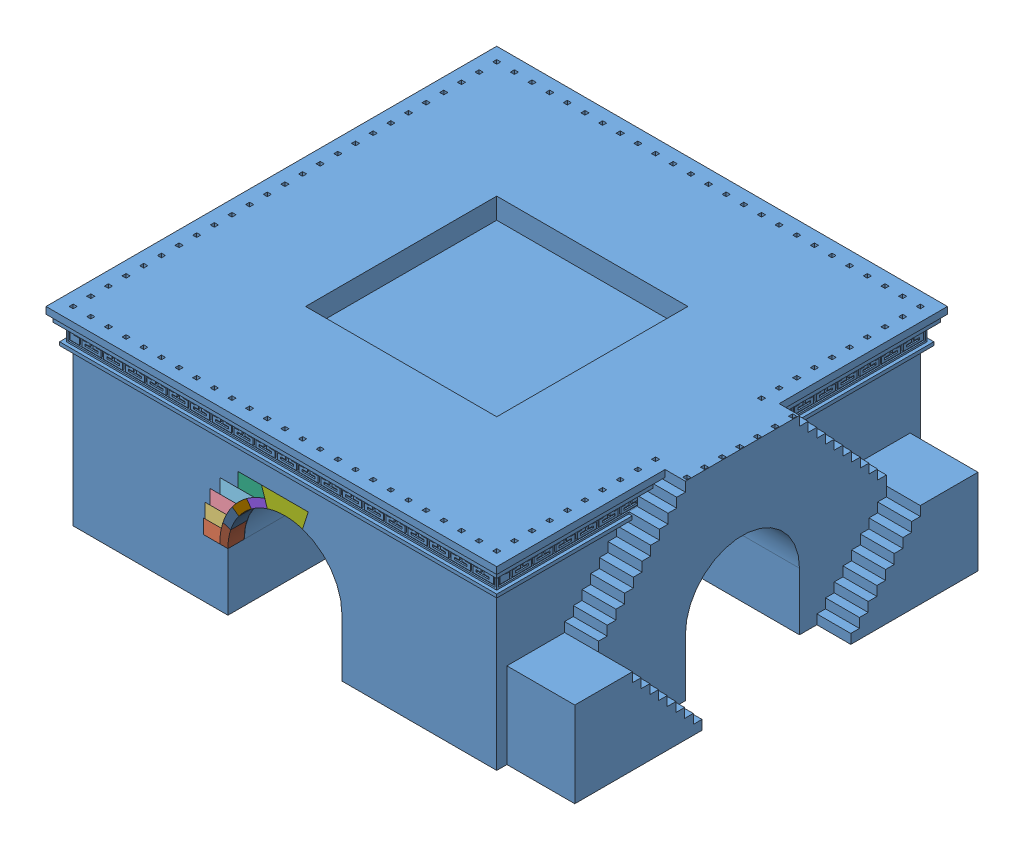
SolidWorks assembly 底座拱门装配, configuration 默认. Lengths in mm.
Overall size (19344 7280 17264).
11 component instances, 11 part files, 30 mates.
Components (placement in the parent):
- 底座整体-1: 底座整体 [默认] at (4568.5731 -4637.1277 26832) size (19344 7280 17264)
- K侧砖1-1: K侧砖1 [默认] at (4568.5731 -7419.1277 26832) size (685.62 551.2 624)
- K侧砖2-1: K侧砖2 [默认] at (4568.5731 -7419.1277 26832) size (819.02 551.2 624)
- K侧砖3-1: K侧砖3 [默认] at (4568.5731 -7419.1277 26832) size (993.7 551.2 624)
- K侧砖4-1: K侧砖4 [默认] at (4568.5731 -7419.1277 26832) size (1323.67 551.2 624)
- K侧砖5-1: K侧砖5 [默认] at (4568.5731 -7419.1277 26832) size (1022.68 551.2 624)
- K砖-1: K砖 [默认] at (4568.5731 -7419.1277 26832) size (1790.96 678.89 624)
- K砖1-1: K砖1 [默认] at (4568.5731 -7419.1277 26832) size (792.22 606.94 624)
- K砖2-1: K砖2 [默认] at (4568.5731 -7419.1277 26832) size (735.58 735.58 624)
- K砖3-1: K砖3 [默认] at (4568.5731 -7419.1277 26832) size (606.94 792.22 624)
- K砖4-1: K砖4 [默认] at (4568.5731 -7419.1277 26832) size (418.89 771.31 624)
Mates (geometry in assembly coordinates):
- 同心12: concentric: cylinder of K砖-1 through (-3543.4269 -2427.1277 28600) axis (0 0 -1) radius 2184; cylinder of K砖1-1 through (-3543.4269 -2427.1277 28600) axis (0 0 -1) radius 2184
- 重合18: coincident: plane of K砖-1 through (-1301.6878 -9326.4911 28600) normal (-0.951057 -0.309017 0); plane of K砖1-1 through (-1301.6878 -9326.4911 28600) normal (0.951057 0.309017 0)
- 重合20: coincident: plane of K砖-1 through (4568.5731 -7419.1277 26832) normal (0 0 -1); plane of K砖1-1 through (4568.5731 -7419.1277 26832) normal (0 0 -1)
- 重合21: coincident: plane of K侧砖5-1 through (4568.5731 328.8723 27456) normal (0 1 0); plane of K砖-1 through (4568.5731 328.8723 27456) normal (0 1 0)
- 重合22: coincident: plane of K侧砖5-1 through (-1301.6878 -9326.4911 27456) normal (0.951057 0.309017 0); plane of K砖-1 through (-1301.6878 -9326.4911 27456) normal (-0.951057 -0.309017 0)
- 重合23: coincident: plane of K侧砖5-1 through (4568.5731 -7419.1277 27456) normal (0 0 1); plane of K砖-1 through (4568.5731 -7419.1277 27456) normal (0 0 1)
- 同心13: concentric: cylinder of K侧砖4-1 through (-3543.4269 -2427.1277 27456) axis (0 0 -1) radius 2496; cylinder of K砖1-1 through (-3543.4269 -2427.1277 27456) axis (0 0 -1) radius 2496
- 重合24: coincident: plane of K侧砖4-1 through (4568.5731 -222.3277 27456) normal (0 1 0); plane of K侧砖5-1 through (4568.5731 -222.3277 27456) normal (0 -1 0)
- 重合25: coincident: plane of K侧砖4-1 through (4568.5731 -7419.1277 26832) normal (0 0 -1); plane of K侧砖5-1 through (4568.5731 -7419.1277 26832) normal (0 0 -1)
- 重合26: coincident: plane of K砖1-1 through (1633.0373 -9551.9193 27456) normal (-0.809017 -0.587785 0); plane of K砖2-1 through (1633.0373 -9551.9193 27456) normal (0.809017 0.587785 0)
- 同心14: concentric: cylinder of K侧砖4-1 through (-3543.4269 -2427.1277 27456) axis (0 0 -1) radius 2496; cylinder of K砖2-1 through (-3543.4269 -2427.1277 27456) axis (0 0 -1) radius 2496
- 重合27: coincident: plane of K砖1-1 through (4568.5731 -7419.1277 27456) normal (0 0 1); plane of K砖2-1 through (4568.5731 -7419.1277 27456) normal (0 0 1)
- 重合28: coincident: plane of K砖2-1 through (4139.7831 -8009.3065 27456) normal (-0.587785 -0.809017 0); plane of K砖3-1 through (4139.7831 -8009.3065 27456) normal (0.587785 0.809017 0)
- 同心15: concentric: cylinder of K砖2-1 through (-3543.4269 -2427.1277 27456) axis (0 0 -1) radius 2184; cylinder of K砖3-1 through (-3543.4269 -2427.1277 27456) axis (0 0 -1) radius 2184
- 重合29: coincident: plane of K砖2-1 through (4568.5731 -7419.1277 27456) normal (0 0 1); plane of K砖3-1 through (4568.5731 -7419.1277 27456) normal (0 0 1)
- 同心16: concentric: cylinder of K侧砖3-1 through (-3543.4269 -2427.1277 27456) axis (0 0 -1) radius 2496; cylinder of K砖2-1 through (-3543.4269 -2427.1277 27456) axis (0 0 -1) radius 2496
- 重合30: coincident: plane of K侧砖3-1 through (4568.5731 -7419.1277 27456) normal (0 0 1); plane of K侧砖4-1 through (4568.5731 -7419.1277 27456) normal (0 0 1)
- 重合31: coincident: plane of K侧砖3-1 through (4568.5731 -773.5277 27456) normal (0 1 0); plane of K侧砖4-1 through (4568.5731 -773.5277 27456) normal (0 -1 0)
- 同心17: concentric: cylinder of K侧砖2-1 through (-3543.4269 -2427.1277 27456) axis (0 0 -1) radius 2496; cylinder of K砖3-1 through (-3543.4269 -2427.1277 27456) axis (0 0 -1) radius 2496
- 重合32: coincident: plane of K侧砖2-1 through (4568.5731 -1324.7277 27456) normal (0 1 0); plane of K侧砖3-1 through (4568.5731 -1324.7277 27456) normal (0 -1 0)
- 重合33: coincident: plane of K侧砖2-1 through (4568.5731 -7419.1277 27456) normal (0 0 1); plane of K侧砖3-1 through (4568.5731 -7419.1277 27456) normal (0 0 1)
- 重合34: coincident: plane of K砖3-1 through (5261.058 -5287.8782 27456) normal (-0.309017 -0.951057 0); plane of K砖4-1 through (5261.058 -5287.8782 27456) normal (0.309017 0.951057 0)
- 同心18: concentric: cylinder of K侧砖2-1 through (-3543.4269 -2427.1277 27456) axis (0 0 -1) radius 2496; cylinder of K砖4-1 through (-3543.4269 -2427.1277 27456) axis (0 0 -1) radius 2496
- 重合35: coincident: plane of K砖3-1 through (4568.5731 -7419.1277 27456) normal (0 0 1); plane of K砖4-1 through (4568.5731 -7419.1277 27456) normal (0 0 1)
- 同心19: concentric: cylinder of K侧砖1-1 through (-3543.4269 -2427.1277 27456) axis (0 0 -1) radius 2496; cylinder of K砖4-1 through (-3543.4269 -2427.1277 27456) axis (0 0 -1) radius 2496
- 重合36: coincident: plane of K侧砖1-1 through (4568.5731 -1875.9277 27456) normal (0 1 0); plane of K侧砖2-1 through (4568.5731 -1875.9277 27456) normal (0 -1 0)
- 重合37: coincident: plane of K侧砖1-1 through (4568.5731 -7419.1277 27456) normal (0 0 1); plane of K侧砖2-1 through (4568.5731 -7419.1277 27456) normal (0 0 1)
- 重合38: coincident: plane of 底座整体-1 through (4568.5731 328.8723 27456) normal (0 -1 0); plane of K砖-1 through (4568.5731 328.8723 27456) normal (0 1 0)
- 同心20: concentric: cylinder of 底座整体-1 through (-3543.4269 -2427.1277 11232) axis (0 0 1) radius 2184; cylinder of K砖2-1 through (-3543.4269 -2427.1277 27456) axis (0 0 -1) radius 2184
- 重合39: coincident: plane of 底座整体-1 through (4568.5731 -4637.1277 26832) normal (0 0 1); plane of K砖-1 through (4568.5731 -7419.1277 26832) normal (0 0 -1)
